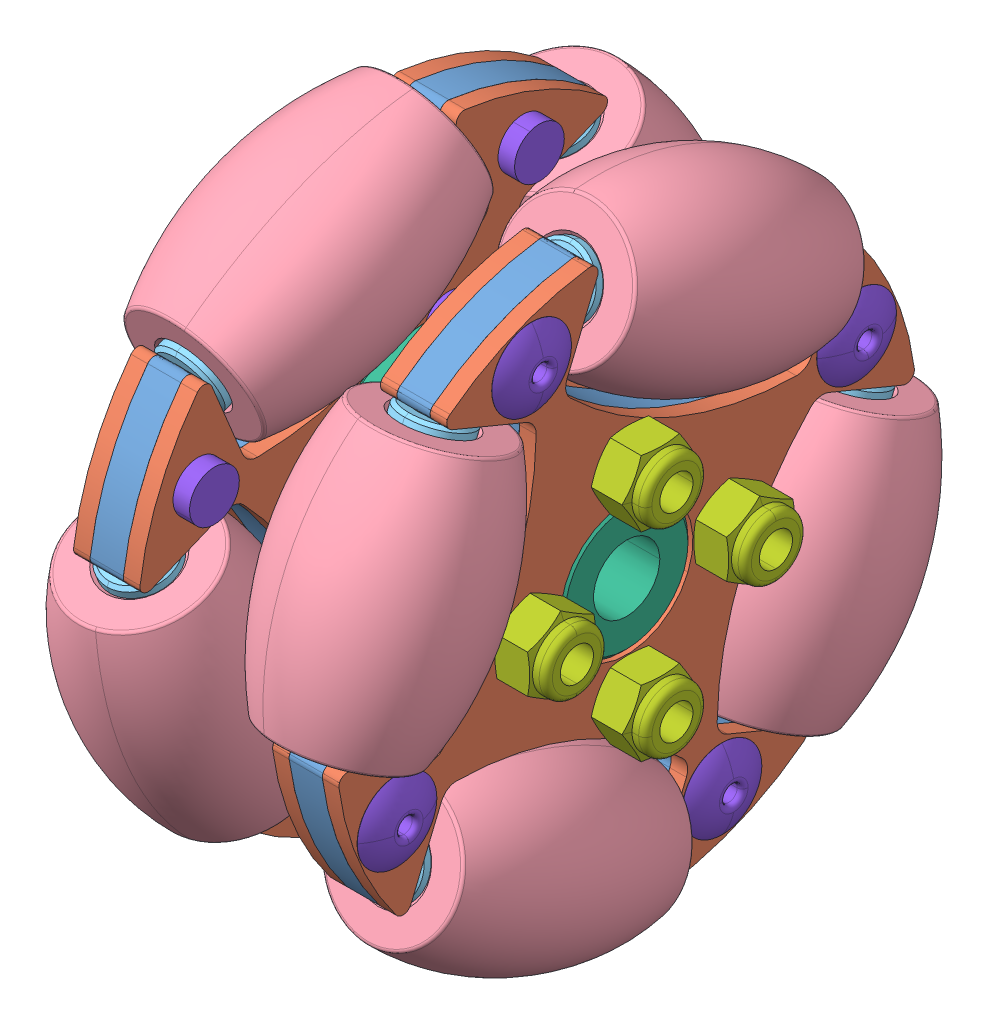
SolidWorks assembly 14166, configuration Default. Lengths in mm.
Overall size (25.23 48.71 48.71).
54 component instances, 8 part files, 0 mates.
Components (placement in the parent):
- 14166.STEP-1: 14166.STEP [Default] at origin size (25.23 48.71 48.71)
  - 1.STEP-1: 1.STEP [Default] at (-2.5516 2.6832 -19.3277) x (0 0.382683 -0.92388) z (1 0 0) size (40.33 40.33 13.23)
    - 1.5__90__________.STEP-1: 1.5__90__________.STEP [Default] at (-211460.3443 -8818.4904 0) size (30.44 30.44 2)
    - 1.5__90____________.STEP-1: 1.5__90____________.STEP [Default] at (-211558.6342 -8818.8281 1.5) size (30.44 30.44 1)
    - 1.5__90____________.STEP-2: 1.5__90____________.STEP [Default] at (-211558.6342 -8818.8281 -1.5) size (30.44 30.44 1)
    - 1.5__90__________-0.STEP-1: 1.5__90__________-0.STEP [Default] at (-211387.6686 26.0495 -8888.2004) x (1 0 0) z (0 -1 0) size (17.5 2 2)
    - 1.5__90________.STEP-1: 1.5__90________.STEP [Default] at (-211171.6508 -2018.6488 8652.3403) x (1 0 0) z (0 0.973195 0.229983) size (15 11 11)
    - 1.5__90__________-1.STEP-1: 1.5__90__________-1.STEP [Default] at (-211243.0998 26.0495 -8888.4077) x (1 0 0) z (0 -1 0) size (6 4 4)
    - 1.5__90__________-1.STEP-2: 1.5__90__________-1.STEP [Default] at (-211233.1998 26.0495 -8888.4077) x (1 0 0) z (0 -1 0) size (6 4 4)
    - 1.5__90__________-0.STEP-2: 1.5__90__________-0.STEP [Default] at (-29.2927 -211359.4264 -8888.2004) x (0 1 0) z (1 0 0) size (17.5 2 2)
    - 1.5__90__________-0.STEP-3: 1.5__90__________-0.STEP [Default] at (211356.1832 -1.0505 -8888.2004) x (-1 0 0) z (0 1 0) size (17.5 2 2)
    - 1.5__90__________-0.STEP-4: 1.5__90__________-0.STEP [Default] at (-2.1927 211384.4254 -8888.2004) x (0 -1 0) z (-1 0 0) size (17.5 2 2)
    - 1.5__90__________-1.STEP-3: 1.5__90__________-1.STEP [Default] at (-29.2927 -211214.8576 -8888.4077) x (0 1 0) z (1 0 0) size (6 4 4)
    - 1.5__90__________-1.STEP-4: 1.5__90__________-1.STEP [Default] at (211211.6144 -1.0505 -8888.4077) x (-1 0 0) z (0 1 0) size (6 4 4)
    - 1.5__90__________-1.STEP-5: 1.5__90__________-1.STEP [Default] at (-2.1927 211239.8566 -8888.4077) x (0 -1 0) z (-1 0 0) size (6 4 4)
    - 1.5__90__________-1.STEP-6: 1.5__90__________-1.STEP [Default] at (-29.2927 -211204.9576 -8888.4077) x (0 1 0) z (1 0 0) size (6 4 4)
    - 1.5__90__________-1.STEP-7: 1.5__90__________-1.STEP [Default] at (211201.7144 -1.0505 -8888.4077) x (-1 0 0) z (0 1 0) size (6 4 4)
    - 1.5__90__________-1.STEP-8: 1.5__90__________-1.STEP [Default] at (-2.1927 211229.9566 -8888.4077) x (0 -1 0) z (-1 0 0) size (6 4 4)
    - 1.5__90________.STEP-2: 1.5__90________.STEP [Default] at (2015.4056 -211143.4086 8652.3403) x (0 1 0) z (-0.973195 0 0.229983) size (15 11 11)
    - 1.5__90________.STEP-3: 1.5__90________.STEP [Default] at (211140.1654 2043.6477 8652.3403) x (-1 0 0) z (0 -0.973195 0.229983) size (15 11 11)
    - 1.5__90________.STEP-4: 1.5__90________.STEP [Default] at (-2046.8909 211168.4076 8652.3403) x (0 -1 0) z (0.973195 0 0.229983) size (15 11 11)
  - 1.STEP-2: 1.STEP [Default] at (9.4484 13.7303 -19.3277) x (0 -0.382683 -0.92388) z (-1 0 0) size (40.33 40.33 13.23)
    - 1.5__90__________.STEP-1: 1.5__90__________.STEP [Default] at (-211460.3443 -8818.4904 0) size (30.44 30.44 2)
    - 1.5__90____________.STEP-1: 1.5__90____________.STEP [Default] at (-211558.6342 -8818.8281 1.5) size (30.44 30.44 1)
    - 1.5__90____________.STEP-2: 1.5__90____________.STEP [Default] at (-211558.6342 -8818.8281 -1.5) size (30.44 30.44 1)
    - 1.5__90__________-0.STEP-1: 1.5__90__________-0.STEP [Default] at (-211387.6686 26.0495 -8888.2004) x (1 0 0) z (0 -1 0) size (17.5 2 2)
    - 1.5__90________.STEP-1: 1.5__90________.STEP [Default] at (-211171.6508 -2018.6488 8652.3403) x (1 0 0) z (0 0.973195 0.229983) size (15 11 11)
    - 1.5__90__________-1.STEP-1: 1.5__90__________-1.STEP [Default] at (-211243.0998 26.0495 -8888.4077) x (1 0 0) z (0 -1 0) size (6 4 4)
    - 1.5__90__________-1.STEP-2: 1.5__90__________-1.STEP [Default] at (-211233.1998 26.0495 -8888.4077) x (1 0 0) z (0 -1 0) size (6 4 4)
    - 1.5__90__________-0.STEP-2: 1.5__90__________-0.STEP [Default] at (-29.2927 -211359.4264 -8888.2004) x (0 1 0) z (1 0 0) size (17.5 2 2)
    - 1.5__90__________-0.STEP-3: 1.5__90__________-0.STEP [Default] at (211356.1832 -1.0505 -8888.2004) x (-1 0 0) z (0 1 0) size (17.5 2 2)
    - 1.5__90__________-0.STEP-4: 1.5__90__________-0.STEP [Default] at (-2.1927 211384.4254 -8888.2004) x (0 -1 0) z (-1 0 0) size (17.5 2 2)
    - 1.5__90__________-1.STEP-3: 1.5__90__________-1.STEP [Default] at (-29.2927 -211214.8576 -8888.4077) x (0 1 0) z (1 0 0) size (6 4 4)
    - 1.5__90__________-1.STEP-4: 1.5__90__________-1.STEP [Default] at (211211.6144 -1.0505 -8888.4077) x (-1 0 0) z (0 1 0) size (6 4 4)
    - 1.5__90__________-1.STEP-5: 1.5__90__________-1.STEP [Default] at (-2.1927 211239.8566 -8888.4077) x (0 -1 0) z (-1 0 0) size (6 4 4)
    - 1.5__90__________-1.STEP-6: 1.5__90__________-1.STEP [Default] at (-29.2927 -211204.9576 -8888.4077) x (0 1 0) z (1 0 0) size (6 4 4)
    - 1.5__90__________-1.STEP-7: 1.5__90__________-1.STEP [Default] at (211201.7144 -1.0505 -8888.4077) x (-1 0 0) z (0 1 0) size (6 4 4)
    - 1.5__90__________-1.STEP-8: 1.5__90__________-1.STEP [Default] at (-2.1927 211229.9566 -8888.4077) x (0 -1 0) z (-1 0 0) size (6 4 4)
    - 1.5__90________.STEP-2: 1.5__90________.STEP [Default] at (2015.4056 -211143.4086 8652.3403) x (0 1 0) z (-0.973195 0 0.229983) size (15 11 11)
    - 1.5__90________.STEP-3: 1.5__90________.STEP [Default] at (211140.1654 2043.6477 8652.3403) x (-1 0 0) z (0 -0.973195 0.229983) size (15 11 11)
    - 1.5__90________.STEP-4: 1.5__90________.STEP [Default] at (-2046.8909 211168.4076 8652.3403) x (0 -1 0) z (0.973195 0 0.229983) size (15 11 11)
  - 1.5__90__________-2.STEP-1: 1.5__90__________-2.STEP [Default] at (-211301.1907 -8828.5722 0) size (16 15.5 15.5)
  - ________M2.STEP-1: ________M2.STEP [Default] at (11.4484 2.2067 0) x (0 -1 0) z (0 0 1) size (4.01 3 4.63)
  - ____2X4.STEP-1: ____2X4.STEP [Default] at (-2.2958 -5.6515 -5.7403) x (0 -1 0) z (0 0 1) size (4.8 5.72 4.8)
  - ____2X4.STEP-2: ____2X4.STEP [Default] at (9.1927 -5.6515 5.7403) x (0 -0.381849 0.924225) z (0 -0.924225 -0.381849) size (4.8 5.72 4.8)
  - ________M2.STEP-2: ________M2.STEP [Default] at (11.4484 8.2067 -6) x (0 0 -1) z (0 -1 0) size (4.01 3 4.63)
  - ________M2.STEP-3: ________M2.STEP [Default] at (11.4484 14.2067 0) x (0 1 0) z (0 0 -1) size (4.01 3 4.63)
  - ________M2.STEP-4: ________M2.STEP [Default] at (11.4484 8.2067 6) x (0 0 1) z (0 1 0) size (4.01 3 4.63)
  - ____2X4.STEP-3: ____2X4.STEP [Default] at (-2.2958 13.947 -13.8582) x (0 0 -1) z (0 -1 0) size (4.8 5.72 4.8)
  - ____2X4.STEP-4: ____2X4.STEP [Default] at (-2.2958 22.0649 5.7403) x (0 1 0) z (0 0 -1) size (4.8 5.72 4.8)
  - ____2X4.STEP-5: ____2X4.STEP [Default] at (-2.2958 2.4665 13.8582) x (0 0 1) z (0 1 0) size (4.8 5.72 4.8)
  - ____2X4.STEP-6: ____2X4.STEP [Default] at (9.1927 2.4665 -13.8582) x (0 -0.924225 -0.381849) z (0 0.381849 -0.924225) size (4.8 5.72 4.8)
  - ____2X4.STEP-7: ____2X4.STEP [Default] at (9.1927 22.0649 -5.7403) x (0 0.381849 -0.924225) z (0 0.924225 0.381849) size (4.8 5.72 4.8)
  - ____2X4.STEP-8: ____2X4.STEP [Default] at (9.1927 13.947 13.8582) x (0 0.924225 0.381849) z (0 -0.381849 0.924225) size (4.8 5.72 4.8)
